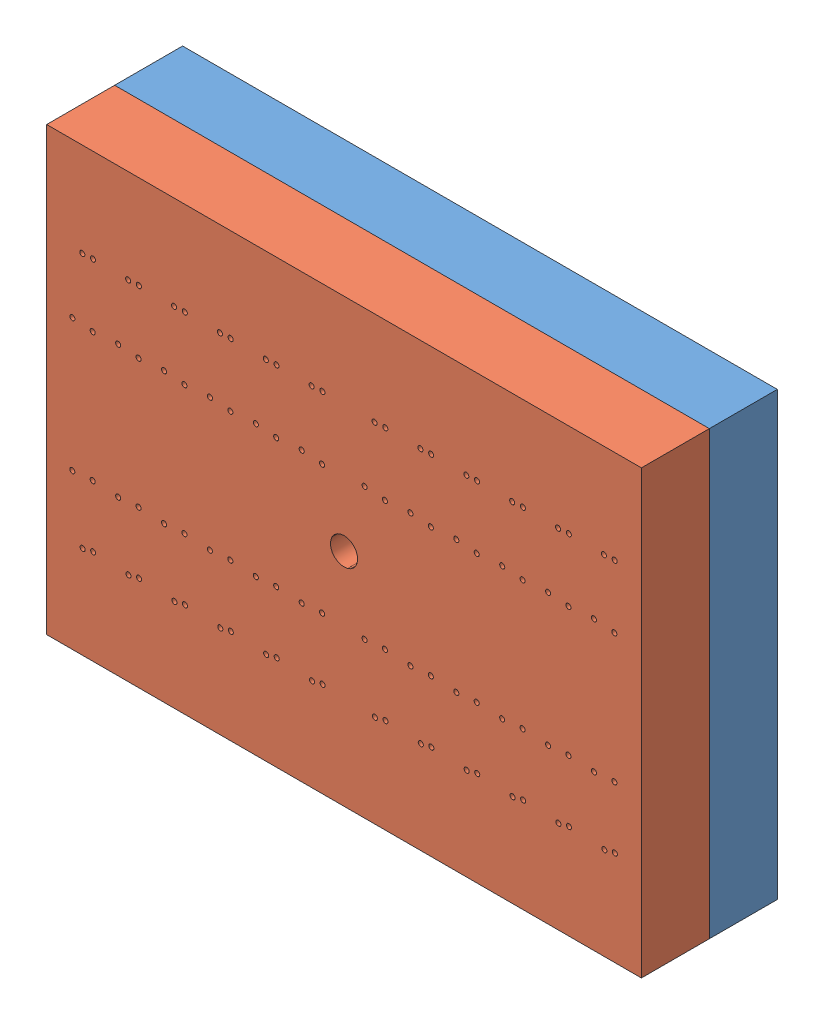
SolidWorks assembly Montagem Bloco, configuration Valor predeterminado. Lengths in mm.
Overall size (350 260 80).
26 component instances, 3 part files, 10 mates.
Components (placement in the parent):
- Cavidade Inferior-1: Cavidade Inferior [Valor predeterminado] at origin size (350 260 40)
- Cavidade Superior-1: Cavidade Superior [Valor predeterminado] at (0 0 40) size (350 260 40.19)
- Grampo com Contração-1: Grampo com Contração [Valor predeterminado] at (-145 99.4421 20) x (0 -1 0) z (0 0 1) size (72.81 19.67 8.12)
- Grampo com Contração-2: Grampo com Contração [Valor predeterminado] at (-152.3384 -99.9621 20) x (-0.169907 0.98546 0) z (0 0 1) size (72.81 19.67 8.12)
- Grampo com Contração-3: Grampo com Contração [Valor predeterminado] at (-125.3384 -99.9621 20) x (-0.169907 0.98546 0) z (0 0 1) size (72.81 19.67 8.12)
- Grampo com Contração-4: Grampo com Contração [Valor predeterminado] at (-98.3384 -99.9621 20) x (-0.169907 0.98546 0) z (0 0 1) size (72.81 19.67 8.12)
- Grampo com Contração-5: Grampo com Contração [Valor predeterminado] at (-71.3384 -99.9621 20) x (-0.169907 0.98546 0) z (0 0 1) size (72.81 19.67 8.12)
- Grampo com Contração-6: Grampo com Contração [Valor predeterminado] at (-44.3384 -99.9621 20) x (-0.169907 0.98546 0) z (0 0 1) size (72.81 19.67 8.12)
- Grampo com Contração-7: Grampo com Contração [Valor predeterminado] at (-17.3384 -99.9621 20) x (-0.169907 0.98546 0) z (0 0 1) size (72.81 19.67 8.12)
- Grampo com Contração-12: Grampo com Contração [Valor predeterminado] at (-118 99.4421 20) x (0 -1 0) z (0 0 1) size (72.81 19.67 8.12)
- Grampo com Contração-13: Grampo com Contração [Valor predeterminado] at (-91 99.4421 20) x (0 -1 0) z (0 0 1) size (72.81 19.67 8.12)
- Grampo com Contração-14: Grampo com Contração [Valor predeterminado] at (-64 99.4421 20) x (0 -1 0) z (0 0 1) size (72.81 19.67 8.12)
- Grampo com Contração-15: Grampo com Contração [Valor predeterminado] at (-37 99.4421 20) x (0 -1 0) z (0 0 1) size (72.81 19.67 8.12)
- Grampo com Contração-16: Grampo com Contração [Valor predeterminado] at (-10 99.4421 20) x (0 -1 0) z (0 0 1) size (72.81 19.67 8.12)
- Grampo com Contração-25: Grampo com Contração [Valor predeterminado] at (19.6616 -99.9621 20) x (-0.169907 0.98546 0) z (0 0 1) size (72.81 19.67 8.12)
- Grampo com Contração-26: Grampo com Contração [Valor predeterminado] at (46.6616 -99.9621 20) x (-0.169907 0.98546 0) z (0 0 1) size (72.81 19.67 8.12)
- Grampo com Contração-27: Grampo com Contração [Valor predeterminado] at (73.6616 -99.9621 20) x (-0.169907 0.98546 0) z (0 0 1) size (72.81 19.67 8.12)
- Grampo com Contração-28: Grampo com Contração [Valor predeterminado] at (100.6616 -99.9621 20) x (-0.169907 0.98546 0) z (0 0 1) size (72.81 19.67 8.12)
- Grampo com Contração-29: Grampo com Contração [Valor predeterminado] at (127.6616 -99.9621 20) x (-0.169907 0.98546 0) z (0 0 1) size (72.81 19.67 8.12)
- Grampo com Contração-30: Grampo com Contração [Valor predeterminado] at (154.6616 -99.9621 20) x (-0.169907 0.98546 0) z (0 0 1) size (72.81 19.67 8.12)
- Grampo com Contração-31: Grampo com Contração [Valor predeterminado] at (27 99.4421 20) x (0 -1 0) z (0 0 1) size (72.81 19.67 8.12)
- Grampo com Contração-32: Grampo com Contração [Valor predeterminado] at (54 99.4421 20) x (0 -1 0) z (0 0 1) size (72.81 19.67 8.12)
- Grampo com Contração-33: Grampo com Contração [Valor predeterminado] at (81 99.4421 20) x (0 -1 0) z (0 0 1) size (72.81 19.67 8.12)
- Grampo com Contração-34: Grampo com Contração [Valor predeterminado] at (108 99.4421 20) x (0 -1 0) z (0 0 1) size (72.81 19.67 8.12)
- Grampo com Contração-35: Grampo com Contração [Valor predeterminado] at (135 99.4421 20) x (0 -1 0) z (0 0 1) size (72.81 19.67 8.12)
- Grampo com Contração-36: Grampo com Contração [Valor predeterminado] at (162 99.4421 20) x (0 -1 0) z (0 0 1) size (72.81 19.67 8.12)
Mates (geometry in assembly coordinates):
- Coincidente2: coordinate: point of Cavidade Inferior-1
- Coincidente3: coincident anti-aligned: plane of Cavidade Inferior-1 through (0 0 20) normal (0 0 1); plane of Cavidade Superior-1 through (0 0 20) normal (0 0 -1)
- Coincidente4: coincident: plane of Cavidade Inferior-1 through (-175 -130 -20) normal (-1 0 0); plane of Cavidade Superior-1 through (-175 -130 20) normal (-1 0 0)
- Coincidente5: coincident aligned: plane of Cavidade Inferior-1 through (-175 130 -20) normal (0 1 0); plane of Cavidade Superior-1 through (-175 130 20) normal (0 1 0)
- Coincidente6: coincident aligned: plane of Cavidade Inferior-1 through (0 0 20) normal (0 0 1); plane of Grampo com Contração-1 through (-145 99.4421 20) normal (0 0 1)
- Distância1: distance = 30 mm anti-aligned: plane of Grampo com Contração-1 through (-145 99.4421 20) normal (1 0 0); plane of Cavidade Inferior-1 through (-175 -130 -20) normal (-1 0 0)
- Coincidente9: coincident aligned: plane of Cavidade Inferior-1 through (0 0 20) normal (0 0 1); plane of Grampo com Contração-2 through (-152.3384 -99.9621 20) normal (0 0 1)
- Distância2: distance = 30 mm aligned: plane of Grampo com Contração-1 through (-146.2519 100 24.06) normal (0 1 0); plane of Cavidade Inferior-1 through (-175 130 -20) normal (0 1 0)
- Distância3: distance = 30 mm aligned: plane of Grampo com Contração-2 through (-145.9117 -100 24.06) normal (0 -1 0); plane of Cavidade Inferior-1 through (-175 -130 -20) normal (0 -1 0)
- Coincidente12: coincident aligned: plane of Grampo com Contração-1 through (-144.8967 54.325 24.06) normal (1 0 0); plane of Grampo com Contração-2 through (-144.8967 -54.325 24.06) normal (1 0 0)
